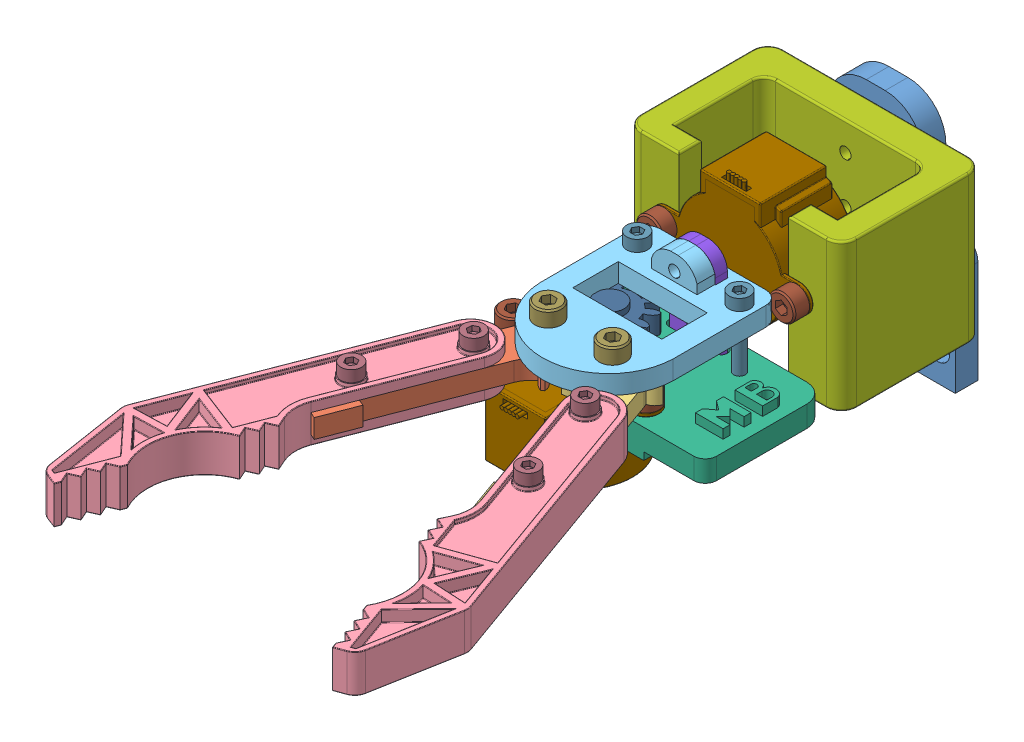
SolidWorks assembly Gripper, configuration Predeterminado. Lengths in mm.
Overall size (107.37 60 185.36).
24 component instances, 14 part files, 51 mates.
Components (placement in the parent):
- P27-1: P27 [Predeterminado] at (-1.6246 -33.1243 60) size (42 60 6)
- Part1 T307-1: Part1 T307 [Default] at (-10.3684 0.7421 144.1334) x (0 1 0) z (-0.933138 0 -0.359519) size (5 59.86 18.15)
- Part2 T307-1: Part2 T307 [Default] at (7.0515 1.4548 144.2044) x (0 1 0) z (-0.941194 0 0.337868) size (5 59.63 18.78)
- Part3 T307-1: Part3 T307 [Default] at (3.902 1.0582 160.6462) x (-0.941194 0 0.337868) z (0 1 0) size (17.76 96.5 10.14)
- Part4 T307-1: Part4 T307 [Default] at (-1.5746 8.5582 128) x (1 0 0) z (0 -1 0) size (35 45 11.5)
- Part5 T307-1: Part5 T307 [Default] at (-1.5746 -8.7118 128) x (-1 0 0) z (0 1 0) size (59.6 31.85 14.33)
- Part6 T307-1: Part6 T307 [Default] at (9.9254 -12.0418 103.5) x (0 -1 0) z (1 0 0) size (38.87 37.5 56.9)
- prt0002-1: prt0002 [Predeterminado] at (-1.5746 -2.0418 114.5) x (0 0 -1) z (0 -1 0) size (5.7 12 34)
- Stepper_28BYJ-48-1: Stepper_28BYJ-48 [Predeterminado] at (-9.9289 -25.1118 135.8562) x (0 0 1) z (-1 0 0) size (32.5 29 42)
- Stepper_28BYJ-48-2: Stepper_28BYJ-48 [Predeterminado] at (-1.5746 5.9582 85.5) x (0 1 0) z (1 0 0) size (32.5 29 42)
- Engrane para motor-1: Engrane para motor [Default] at (-10.1676 -4.7083 127.8825) x (0 -1 0) z (0.312513 0 0.949913) size (6.2 18.78 18.78)
- Part3 T307-2: Part3 T307 [Default] at (-7.4349 1.0582 160.707) x (0.933138 0 0.359519) z (0 -1 0) size (17.76 96.5 10.14)
- 4MX10-1: 4MX10 [Predeterminado] at (7.5711 -2.1118 135.8562) x (0 -1 0) z (0 0 1) size (14 7 7)
- 4MX10-2: 4MX10 [Predeterminado] at (-19.0746 5.9582 108.5) x (0 0 -1) z (1 0 0) size (14 7 7)
- 4MX10-3: 4MX10 [Predeterminado] at (15.9254 5.9582 108.5) x (0 0 -1) z (1 0 0) size (14 7 7)
- 4MX10-4: 4MX10 [Predeterminado] at (-27.4289 -2.1118 135.8562) x (0 -1 0) z (0 0 1) size (14 7 7)
- 4M14-1: 4M14 [Predeterminado] at (-10.0746 12.5582 144) x (0 -1 0) z (0 0 1) size (16 7 7)
- 4M14-2: 4M14 [Predeterminado] at (6.9254 12.5582 144) x (0 -1 0) z (0 0 1) size (16 7 7)
- 3MX12-1: 3MX12 [Predeterminado] at (-25.5209 9.0582 180.5302) x (0 -1 0) z (0 0 1) size (15 5.5 5.5)
- 3MX12-2: 3MX12 [Predeterminado] at (-16.533 9.0582 157.2017) x (0 -1 0) z (-0.546944 0 0.837169) size (15 5.5 5.5)
- 3MX12-3: 3MX12 [Predeterminado] at (13.0787 9.0582 157.352) x (0 -1 0) z (0 0 1) size (15 5.5 5.5)
- 3MX12-4: 3MX12 [Predeterminado] at (21.5254 9.0582 180.8818) x (0 -1 0) z (0 0 1) size (15 5.5 5.5)
- 3MX24-1: 3MX24 [Predeterminado] at (11.9254 11.5582 115.5) x (0 -1 0) z (0 0 1) size (27 5.5 5.5)
- 3MX24-2: 3MX24 [Predeterminado] at (-15.0746 11.5582 115.5) x (0 -1 0) z (0 0 1) size (27 5.5 5.5)
Mates (geometry in assembly coordinates):
- Coincidente2: coincident anti-aligned: plane of P27-1 through (-1.6246 -33.1243 66) normal (0 0 1); plane of Part6 T307-1 through (9.9254 -12.0418 66) normal (0 0 -1)
- Coincidente3: coincident aligned: circle of P27-1; circle of Part6 T307-1
- Coincidente4: coincident aligned: circle of P27-1; circle of Part6 T307-1
- Coincidente7: coincident anti-aligned: plane of Part6 T307-1 through (-19.5746 -24.8456 103.5) normal (0 0 1); plane of Stepper_28BYJ-48-2 through (-18.8523 5.9582 103.5) normal (0 0 -1)
- Coincidente8: coincident anti-aligned: plane of Part6 T307-1 through (12.4254 15.4582 103.5) normal (0 0 1); plane of Stepper_28BYJ-48-2 through (15.7031 5.9582 103.5) normal (0 0 -1)
- Coincidente9: coincident anti-aligned: cylinder of Part6 T307-1; cylinder of Stepper_28BYJ-48-2 through (15.9254 5.9582 104.5) axis (0 0 -1) radius 2
- Coincidente10: coincident anti-aligned: circle of Part6 T307-1; cylinder of Stepper_28BYJ-48-2 through (-19.0746 5.9582 104.5) axis (0 0 -1) radius 2
- Coincidente11: coincident anti-aligned: plane of prt0002-1 through (0.4254 -0.5418 113) normal (0 -1 0); plane of Stepper_28BYJ-48-2 through (1.4254 -0.5418 114.5) normal (0 1 0)
- Concéntrica1: concentric anti-aligned: circle of prt0002-1; circle of Stepper_28BYJ-48-2
- Coincidente12: coincident aligned: plane of prt0002-1 through (-1.5746 -2.0418 114.5) normal (0 0 1); plane of Stepper_28BYJ-48-2 through (-1.5746 -2.0418 114.5) normal (0 0 1)
- Coincidente13: coincident anti-aligned: circle of Part5 T307-1; circle of prt0002-1
- Coincidente14: coincident anti-aligned: plane of Part5 T307-1 through (23.2254 -7.1118 114) normal (0 1 0); plane of Stepper_28BYJ-48-1 through (-27.2066 -7.1118 135.8562) normal (0 -1 0)
- Coincidente15: coincident anti-aligned: circle of Part5 T307-1; cylinder of Stepper_28BYJ-48-1 through (-27.4289 -6.1118 135.8562) axis (0 -1 0) radius 2
- Coincidente16: coincident anti-aligned: circle of Part5 T307-1; cylinder of Stepper_28BYJ-48-1 through (7.5711 -6.1118 135.8562) axis (0 -1 0) radius 2
- Coincidente17: coincident aligned: circle of Part4 T307-1; circle of prt0002-1
- Coincidente21: coincident anti-aligned: plane of Part2 T307-1 through (6.9254 3.5582 144) normal (0 1 0); plane of Part4 T307-1 through (-1.5746 3.5582 136.4926) normal (0 -1 0)
- Concéntrica7: concentric anti-aligned: cylinder of Part2 T307-1 through (6.9254 48.5583 144) axis (0 -1 0) radius 3.5; cylinder of Part4 T307-1 through (6.9254 3.5582 144) axis (0 1 0) radius 2
- Coincidente22: coincident anti-aligned: plane of Part1 T307-1 through (-10.0746 3.5582 144) normal (0 1 0); plane of Part4 T307-1 through (-1.5746 3.5582 136.4926) normal (0 -1 0)
- Concéntrica8: concentric anti-aligned: cylinder of Part1 T307-1 through (-10.0746 48.5583 144) axis (0 -1 0) radius 3.5; cylinder of Part4 T307-1 through (-10.0746 3.5582 144) axis (0 1 0) radius 2
- Coincidente23: coincident anti-aligned: plane of Stepper_28BYJ-48-1 through (-9.9289 3.8882 127.8562) normal (0 1 0); plane of Engrane para motor-1 through (-9.935 3.8882 127.855) normal (0 -1 0)
- Concéntrica9: concentric anti-aligned: cylinder of Stepper_28BYJ-48-1 through (-9.9289 -4.6118 127.8562) axis (0 1 0) radius 2.5; cylinder of Engrane para motor-1 through (-9.9289 -0.3118 127.8562) axis (0 -1 0) radius 2.5
- Coincidente25: coincident anti-aligned: plane of Part1 T307-1 through (-10.0746 3.5582 144) normal (0 1 0); plane of Part3 T307-2 through (-18.715 3.5582 181.6405) normal (0 -1 0)
- Concéntrica10: concentric anti-aligned: cylinder of Part1 T307-1 through (-25.5209 3.5592 180.5302) axis (0 -1 0) radius 1.5; cylinder of Part3 T307-2 through (-25.5209 -3.9418 180.5302) axis (0 1 0) radius 1.5
- Concéntrica11: concentric anti-aligned: cylinder of Part1 T307-1 through (-16.533 3.5592 157.2017) axis (0 -1 0) radius 1.5; cylinder of Part3 T307-2 through (-16.533 -3.9418 157.2017) axis (0 1 0) radius 1.5
- Coincidente26: coincident anti-aligned: plane of Part2 T307-1 through (6.9254 3.5582 144) normal (0 1 0); plane of Part3 T307-1 through (14.6957 3.5582 181.8346) normal (0 -1 0)
- Concéntrica12: concentric aligned: cylinder of Part2 T307-1 through (13.0787 3.5592 157.352) axis (0 -1 0) radius 1.5; cylinder of Part3 T307-1 through (13.0787 6.0582 157.352) axis (0 -1 0) radius 1.5
- Concéntrica13: concentric aligned: cylinder of Part2 T307-1 through (21.5254 3.5592 180.8818) axis (0 -1 0) radius 1.5; cylinder of Part3 T307-1 through (21.5254 6.0582 180.8818) axis (0 -1 0) radius 1.5
- Coincidente31: coincident anti-aligned: plane of Stepper_28BYJ-48-1 through (-9.9289 -6.1118 135.8562) normal (0 1 0); plane of 4MX12-4 through (-23.9289 -6.1118 135.8562) normal (0 -1 0)
- Concéntrica18: concentric anti-aligned: cylinder of Stepper_28BYJ-48-1 through (-27.4289 -6.1118 135.8562) axis (0 -1 0) radius 2; cylinder of 4MX12-4 through (-27.4289 -22.1118 135.8562) axis (0 1 0) radius 2
- Coincidente32: coincident anti-aligned: plane of Stepper_28BYJ-48-1 through (-9.9289 -6.1118 135.8562) normal (0 1 0); plane of 4MX12-1 through (11.0711 -6.1118 135.8562) normal (0 -1 0)
- Concéntrica19: concentric anti-aligned: cylinder of Stepper_28BYJ-48-1 through (7.5711 -6.1118 135.8562) axis (0 -1 0) radius 2; cylinder of 4MX12-1 through (7.5711 -22.1118 135.8562) axis (0 1 0) radius 2
- Coincidente33: coincident anti-aligned: plane of Stepper_28BYJ-48-2 through (-1.5746 5.9582 104.5) normal (0 0 1); plane of 4MX12-3 through (15.9254 9.4582 104.5) normal (0 0 -1)
- Concéntrica20: concentric anti-aligned: cylinder of Stepper_28BYJ-48-2 through (15.9254 5.9582 104.5) axis (0 0 -1) radius 2; cylinder of 4MX12-3 through (15.9254 5.9582 88.5) axis (0 0 1) radius 2
- Coincidente35: coincident anti-aligned: plane of Stepper_28BYJ-48-2 through (-1.5746 5.9582 104.5) normal (0 0 1); plane of 4MX12-2 through (-19.0746 9.4582 104.5) normal (0 0 -1)
- Concéntrica22: concentric anti-aligned: cylinder of Stepper_28BYJ-48-2 through (-19.0746 5.9582 104.5) axis (0 0 -1) radius 2; cylinder of 4MX12-2 through (-19.0746 5.9582 88.5) axis (0 0 1) radius 2
- Coincidente37: coincident anti-aligned: plane of Part4 T307-1 through (-1.5746 8.5582 136.4926) normal (0 1 0); plane of 4M14-1 through (-6.5746 8.5582 144) normal (0 -1 0)
- Concéntrica24: concentric aligned: cylinder of Part4 T307-1 through (-10.0746 3.5582 144) axis (0 1 0) radius 2; cylinder of 4M14-1 through (-10.0746 -7.4418 144) axis (0 1 0) radius 2
- Coincidente38: coincident anti-aligned: plane of Part4 T307-1 through (-1.5746 8.5582 136.4926) normal (0 1 0); plane of 4M14-2 through (10.4254 8.5582 144) normal (0 -1 0)
- Concéntrica25: concentric aligned: cylinder of Part4 T307-1 through (6.9254 3.5582 144) axis (0 1 0) radius 2; cylinder of 4M14-2 through (6.9254 -7.4418 144) axis (0 1 0) radius 2
- Coincidente42: coincident aligned: circle of Part3 T307-2; plane of 3MX12-2 through (-14.2307 6.0582 158.7058) normal (0 -1 0)
- Concéntrica29: concentric aligned: cylinder of Part3 T307-2 through (-16.533 -3.9418 157.2017) axis (0 1 0) radius 1.5; cylinder of 3MX12-2 through (-16.533 -3.9418 157.2017) axis (0 1 0) radius 1.5
- Coincidente43: coincident anti-aligned: plane of Part3 T307-2 through (-25.5209 6.0582 180.5302) normal (0 1 0); plane of 3MX12-1 through (-22.7709 6.0582 180.5302) normal (0 -1 0)
- Coincidente44: coincident anti-aligned: plane of Part3 T307-1 through (13.0787 6.0582 157.352) normal (0 1 0); plane of 3MX12-3 through (15.8287 6.0582 157.352) normal (0 -1 0)
- Coincidente45: coincident anti-aligned: plane of Part3 T307-1 through (21.5254 6.0582 180.8818) normal (0 1 0); plane of 3MX12-4 through (24.2754 6.0582 180.8818) normal (0 -1 0)
- Concéntrica30: concentric anti-aligned: cylinder of Part3 T307-1 through (21.5254 6.0582 180.8818) axis (0 -1 0) radius 1.5; cylinder of 3MX12-4 through (21.5254 -3.9418 180.8818) axis (0 1 0) radius 1.5
- Concéntrica31: concentric anti-aligned: cylinder of Part3 T307-1 through (13.0787 6.0582 157.352) axis (0 -1 0) radius 1.5; cylinder of 3MX12-3 through (13.0787 -3.9418 157.352) axis (0 1 0) radius 1.5
- Coincidente46: coincident anti-aligned: plane of Part4 T307-1 through (-1.5746 8.5582 136.4926) normal (0 1 0); plane of 3M30-2 through (-12.3246 8.5582 115.5) normal (0 -1 0)
- Concéntrica32: concentric aligned: cylinder of Part4 T307-1 through (-15.0746 -0.6844 115.5) axis (0 1 0) radius 1.5; cylinder of 3M30-2 through (-15.0746 -1.4418 115.5) axis (0 1 0) radius 1.5
- Coincidente47: coincident anti-aligned: plane of Part4 T307-1 through (-1.5746 8.5582 136.4926) normal (0 1 0); plane of 3M30-1 through (14.6754 8.5582 115.5) normal (0 -1 0)
- Concéntrica33: concentric aligned: cylinder of Part4 T307-1 through (11.9254 -0.6844 115.5) axis (0 1 0) radius 1.5; cylinder of 3M30-1 through (11.9254 -1.4418 115.5) axis (0 1 0) radius 1.5
- Concéntrica35: concentric aligned: cylinder of Part3 T307-2 through (-25.5209 -3.9418 180.5302) axis (0 1 0) radius 1.5; cylinder of 3MX12-1 through (-25.5209 -3.9418 180.5302) axis (0 1 0) radius 1.5
